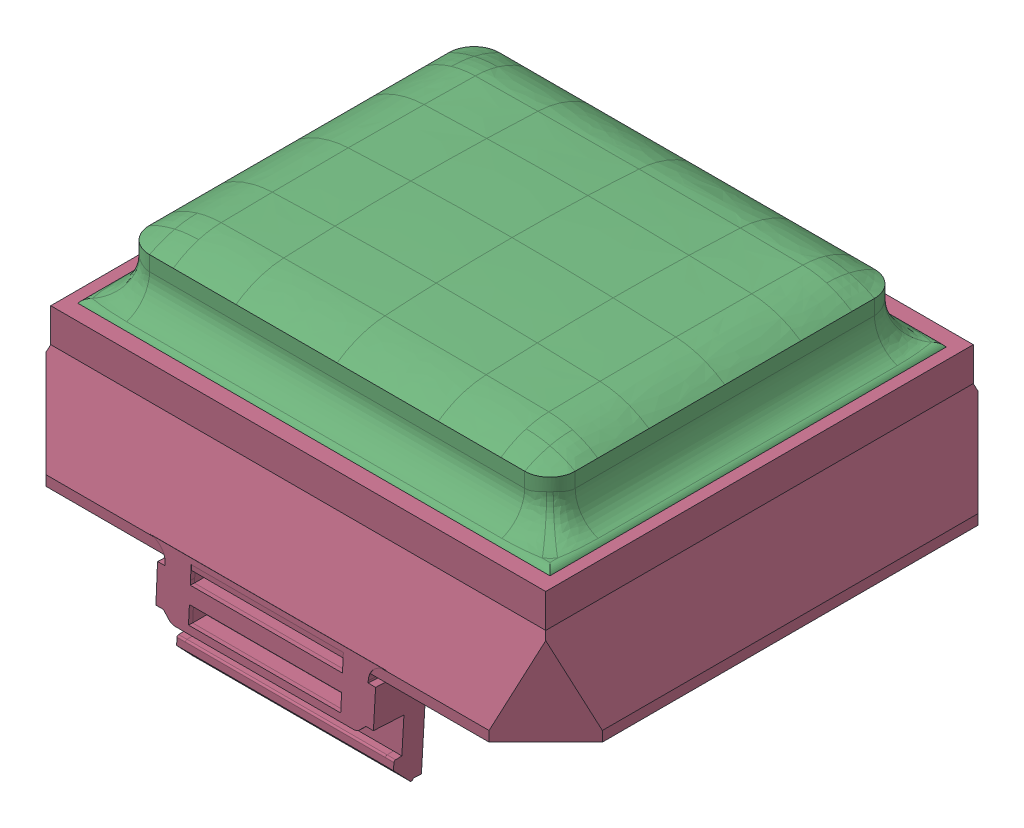
SolidWorks assembly OriginalDesign, configuration 默认. Lengths in mm.
Overall size (33 18.27 29.5).
4 component instances, 4 part files, 10 mates.
Components (placement in the parent):
- Lens-1: OriginLens [默认] at origin size (28.33 2.18 23.83)
- InsideSkin-1: OriginInsideSkin [默认] at (0.0001 0 0.2499) size (23.8 5.48 19.29)
- Topskin-1: OriginTopskin [默认] at (0.0001 2 0.2499) size (28.02 6.25 23.52)
- Supportbase-2: OriginSupportbase [默认] at origin size (33 14.02 29.5)
Mates (geometry in assembly coordinates):
- 同心2: concentric anti-aligned: cylinder of NewInsideSkin_conti-1 through (10.8751 17.7531 8.6249) axis (0 1 0) radius 0.7; cylinder of Board3Con1612611OriginalSkin_TOP-1 through (10.8751 24 8.6249) axis (0 -1 0) radius 0.7
- 同心3: concentric anti-aligned: cylinder of NewInsideSkin_conti-1 through (10.8751 17.7531 -9.1251) axis (0 1 0) radius 0.7; cylinder of Board3Con1612611OriginalSkin_TOP-1 through (10.8751 24 -9.1251) axis (0 -1 0) radius 0.7
- 重合4: coincident aligned: plane of NewInsideSkin_conti-1 through (10.8751 19 -9.1251) normal (0 -1 0); plane of Board3Con1612611OriginalSkin_TOP-1 through (0.0001 19 0.2499) normal (0 -1 0)
- 重合6: coordinate: point of NewContiSupportBase-2
- 重合7: coincident anti-aligned: plane of lensall-1 through (13.75 19 -11.5) normal (0.939693 0.34202 0); plane of NewContiSupportBase-2 through (13.75 19 12.7803) normal (-0.939693 -0.34202 0)
- 同心5: concentric aligned: cylinder of lensall-1 through (13.3294 18.6938 -11.0794) axis (-0.323616 0.889126 0.323616) radius 0.5; cylinder of NewContiSupportBase-2 through (10.7866 25.6801 -8.5366) axis (-0.323616 0.889126 0.323616) radius 0.5
- 重合8: coincident anti-aligned: plane of lensall-1 through (0 18 0) normal (0 -1 0); plane of NewContiSupportBase-2 through (0 18 0) normal (0 1 0)
- 重合9: coincident anti-aligned: plane of lensall-1 through (0 19 0) normal (0 1 0); plane of Board3Con1612611OriginalSkin_TOP-1 through (0.0001 19 0.2499) normal (0 -1 0)
- 重合10: coincident anti-aligned: plane of Board3Con1612611OriginalSkin_TOP-1 through (0.0001 19 11.7499) normal (0 0 1); plane of NewContiSupportBase-2 through (-13.5999 21 11.7499) normal (0 0 -1)
- 重合11: coincident anti-aligned: plane of Board3Con1612611OriginalSkin_TOP-1 through (14.0001 19 0.2499) normal (1 0 0); plane of NewContiSupportBase-2 through (14.0001 21 11.7499) normal (-1 0 0)
